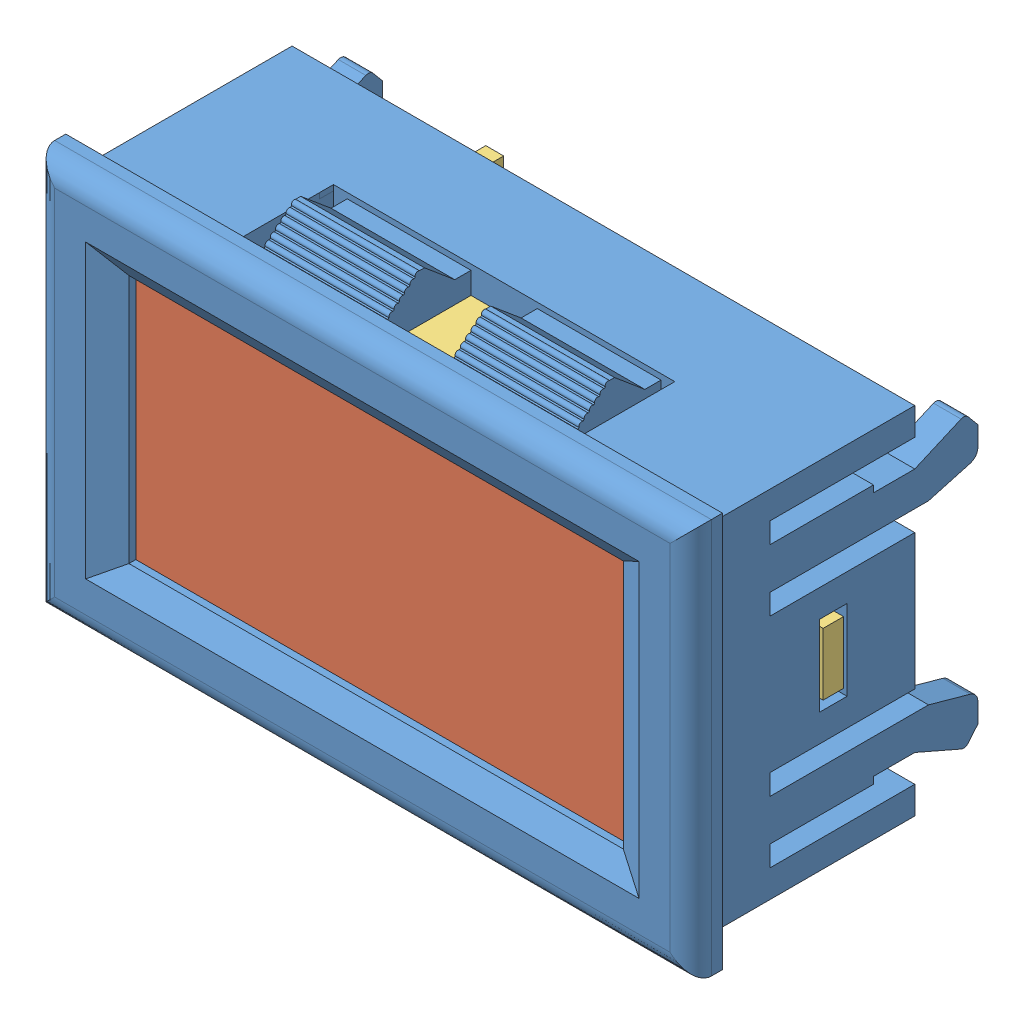
SolidWorks assembly VU FINAL, configuration Valor predeterminado. Lengths in mm.
Overall size (47.75 28.83 22.64).
3 component instances, 3 part files, 0 mates.
Components (placement in the parent):
- PANEL VU-1: PANEL VU [Valor predeterminado] at (-2.1211 3.4853 41.28) size (47.75 28.83 22.12)
- PELICOLA-1: PELICOLA [Valor predeterminado] at (10.5143 -0.0177 56.8069) size (41.28 21.85 0.5)
- PLACA FAKE-1: PLACA FAKE [Valor predeterminado] at (-2.1243 3.4576 55.4655) x (1 0 0) z (0 0 -1) size (45.3 21.94 19.3)
